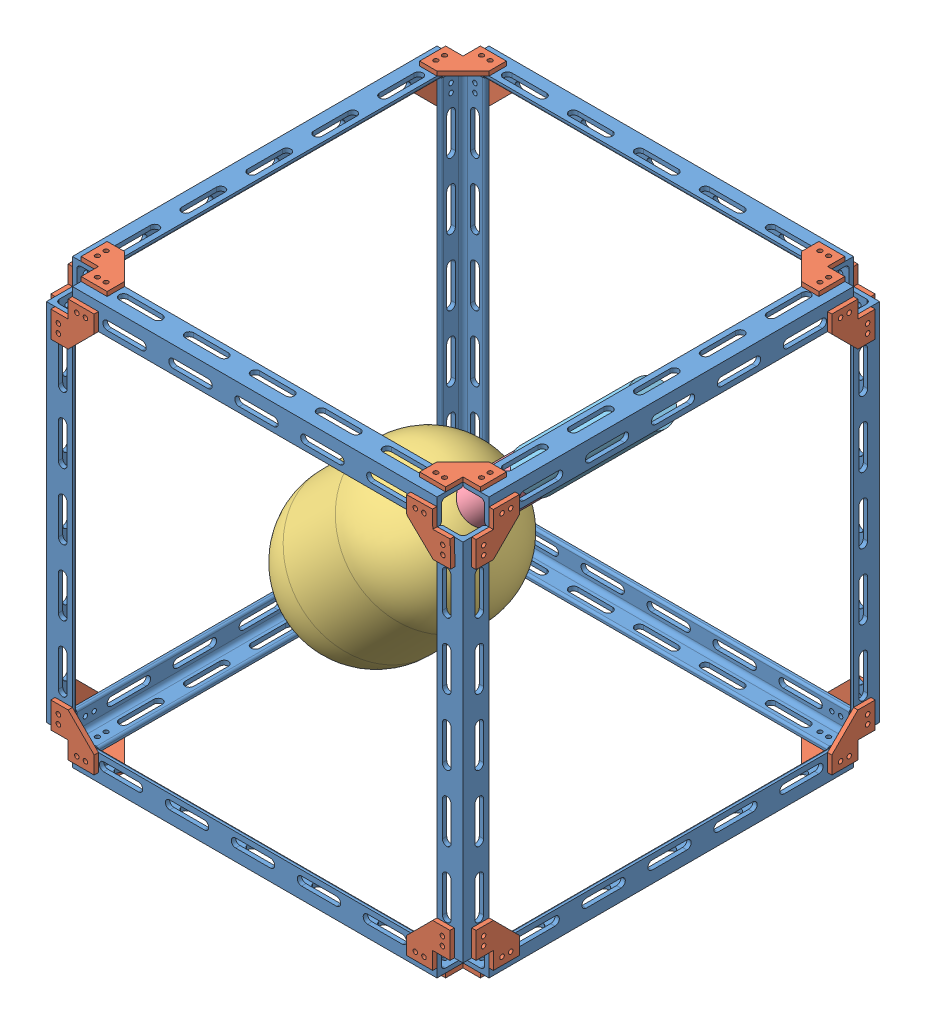
SolidWorks assembly 12 inch with Tank mated, configuration Default. Lengths in mm.
Overall size (334.91 334.91 311.15).
41 component instances, 5 part files, 4 mates.
Components (placement in the parent):
- Outer struct 12 in side length-1: Outer struct 12 in side length [Default] at (-152.3997 0 -152.3996) x (0 0 -1) z (1 0 0) size (311.15 311.15 311.15)
  - WIP 12 inch .75 L rod-1: WIP 12 inch .75 L rod [8982K281] at (-9.525 9.525 0) size (19.05 19.05 266.7)
  - WIP bracket for .75 L bar-1: WIP bracket for .75 L bar [Default] at (-44.4499 -3.175 -146.0502) x (1 0 0.000006) z (-0.000006 0 1) size (31.75 3.17 31.75)
  - WIP 12 inch .75 L rod-2: WIP 12 inch .75 L rod [8982K281] at (-152.4002 9.525 -142.8755) x (0 0 -1) z (1 0 0) size (19.05 19.05 266.7)
  - WIP 12 inch .75 L rod-3: WIP 12 inch .75 L rod [8982K281] at (-9.525 152.3996 -142.8755) x (1 0 0) z (0 -1 0) size (19.05 19.05 266.7)
  - WIP bracket for .75 L bar-2: WIP bracket for .75 L bar [Default] at (0 44.4494 -146.0507) x (0 -1 0.000022) z (0 0.000022 1) size (31.75 3.17 31.75)
  - WIP bracket for .75 L bar-3: WIP bracket for .75 L bar [Default] at (-44.4504 6.3501 -152.4005) x (1 -0.000015 0) z (0.000015 1 0) size (31.75 3.17 31.75)
  - WIP bracket for .75 L bar-4: WIP bracket for .75 L bar [Default] at (-260.3502 298.4499 -152.4005) x (-1 0 0) z (0 -1 0) size (31.75 3.17 31.75)
  - WIP bracket for .75 L bar-5: WIP bracket for .75 L bar [Default] at (-304.8002 260.35 -146.0506) x (0 1 0.000002) z (0 -0.000002 1) size (31.75 3.17 31.75)
  - WIP bracket for .75 L bar-6: WIP bracket for .75 L bar [Default] at (-260.3502 307.9748 -146.0505) x (-1 0 0) z (0 0 1) size (31.75 3.17 31.75)
  - WIP 12 inch .75 L rod-4: WIP 12 inch .75 L rod [8982K281] at (-152.4002 295.2748 -142.8755) x (0 0 -1) z (-1 0 0) size (19.05 19.05 266.7)
  - WIP 12 inch .75 L rod-5: WIP 12 inch .75 L rod [8982K281] at (-295.2752 295.2748 -0.0005) x (-1 0 0) z (0 0 1) size (19.05 19.05 266.7)
  - WIP 12 inch .75 L rod-6: WIP 12 inch .75 L rod [8982K281] at (-295.2752 152.3999 -142.8755) x (-1 0 0) z (0 1 0) size (19.05 19.05 266.7)
  - WIP bracket for .75 L bar-8: WIP bracket for .75 L bar [Default] at (-6.3503 260.3499 -152.4005) x (0.000002 1 0) z (-1 0.000002 0) size (31.75 3.17 31.75)
  - WIP bracket for .75 L bar-9: WIP bracket for .75 L bar [Default] at (-298.4502 44.4499 -152.4005) x (0 -1 0) z (1 0 0) size (31.75 3.17 31.75)
  - WIP bracket for .75 L bar-11: WIP bracket for .75 L bar [Default] at (-6.3505 304.8004 107.9491) x (0.000026 0 1) z (-1 0 0.000026) size (31.75 3.17 31.75)
  - WIP bracket for .75 L bar-12: WIP bracket for .75 L bar [Default] at (-44.4496 298.4506 152.3997) x (1 -0.000013 0) z (-0.000013 -1 0) size (31.75 3.17 31.75)
  - WIP 12 inch .75 L rod-7: WIP 12 inch .75 L rod [8982K281] at (-152.3996 295.2754 142.8747) x (0 0 1) z (1 0 0) size (19.05 19.05 266.7)
  - WIP 12 inch .75 L rod-8: WIP 12 inch .75 L rod [8982K281] at (-9.525 295.2748 -0.0008) x (0 1 0) z (0 0 1) size (19.05 19.05 266.7)
  - WIP bracket for .75 L bar-13: WIP bracket for .75 L bar [Default] at (3.175 298.4493 107.9491) x (0 0.000026 1) z (0 -1 0.000026) size (31.75 3.17 31.75)
  - WIP 12 inch .75 L rod-9: WIP 12 inch .75 L rod [8982K281] at (-9.525 152.4002 142.8747) x (0 0 1) z (0 -1 0) size (19.05 19.05 266.7)
  - WIP bracket for .75 L bar-14: WIP bracket for .75 L bar [Default] at (3.175 260.3496 -146.0505) x (0 1 -0.000009) z (0 0.000009 1) size (31.75 3.17 31.75)
  - WIP bracket for .75 L bar-15: WIP bracket for .75 L bar [Default] at (-298.4499 307.9754 107.9499) x (0.000007 0 1) z (1 0 -0.000007) size (31.75 3.17 31.75)
  - WIP bracket for .75 L bar-16: WIP bracket for .75 L bar [Default] at (-44.4503 304.7998 -146.0503) x (1 0 -0.000013) z (0.000013 0 1) size (31.75 3.17 31.75)
  - WIP bracket for .75 L bar-17: WIP bracket for .75 L bar [Default] at (-6.3497 -3.175 107.9497) x (0.000002 0 1) z (-1 0 0.000002) size (31.75 3.17 31.75)
  - WIP bracket for .75 L bar-18: WIP bracket for .75 L bar [Default] at (3.175 44.4503 146.0496) x (0 -1 0.000013) z (0 -0.000013 -1) size (31.75 3.17 31.75)
  - WIP bracket for .75 L bar-19: WIP bracket for .75 L bar [Default] at (-298.4492 260.3501 152.3997) x (-0.000013 1 0) z (1 0.000013 0) size (31.75 3.17 31.75)
  - WIP bracket for .75 L bar-20: WIP bracket for .75 L bar [Default] at (-304.8002 298.2273 107.8544) x (0 0.017459 0.999848) z (0 -0.999848 0.017459) size (31.75 3.17 31.75)
  - WIP bracket for .75 L bar-21: WIP bracket for .75 L bar [Default] at (-304.7994 44.4499 146.0495) x (0 -1 0) z (0 0 -1) size (31.75 3.17 31.75)
  - WIP 12 inch .75 L rod-11: WIP 12 inch .75 L rod [8982K281] at (-295.2744 152.4002 142.8747) x (-1 0 0) z (0 -1 0) size (19.05 19.05 266.7)
  - WIP bracket for .75 L bar-22: WIP bracket for .75 L bar [Default] at (-260.3497 6.3497 152.3997) x (-1 0.000013 0) z (0.000013 1 0) size (31.75 3.17 31.75)
  - WIP 12 inch .75 L rod-12: WIP 12 inch .75 L rod [8982K281] at (-152.3996 9.525 142.8747) x (0 0 1) z (-1 0 0) size (19.05 19.05 266.7)
  - WIP bracket for .75 L bar-23: WIP bracket for .75 L bar [Default] at (-260.3497 -3.175 146.05) x (-1 0 -0.000013) z (0.000013 0 -1) size (31.75 3.17 31.75)
  - WIP 12 inch .75 L rod-13: WIP 12 inch .75 L rod [8982K281] at (-295.2744 9.525 -0.0004) x (-1 0 0) z (0 0 -1) size (19.05 19.05 266.7)
  - WIP bracket for .75 L bar-24: WIP bracket for .75 L bar [Default] at (-304.8002 6.35 -107.9505) x (0 -0.000004 -1) z (0 1 -0.000004) size (31.75 3.17 31.75)
  - WIP bracket for .75 L bar-25: WIP bracket for .75 L bar [Default] at (-298.4495 -3.175 -107.95) x (-0.000022 0 -1) z (1 0 -0.000022) size (31.75 3.17 31.75)
  - WIP bracket for .75 L bar-26: WIP bracket for .75 L bar [Default] at (-6.3501 44.4503 152.3997) x (0.000013 -1 0) z (-1 -0.000013 0) size (31.75 3.17 31.75)
- LoFi Tank+Reg-1: LoFi Tank+Reg [Default] at (-196.8537 107.9466 0.0003) x (-0.041969 0.041971 0.998237) z (-0.707107 -0.707107 0.000001) size (111.12 111.12 340.27)
  - LoFi Tank-1: LoFi Tank [Default] at origin size (111.12 111.12 163.23)
  - LoFi Reg 1-1: LoFi Reg 1 [Default] at (0 0 -80.6816) x (-0.38598 0.922507 0) z (-0.922507 -0.38598 0) size (28.57 57.15 28.57)
  - LoFi Reg 2-1: LoFi Reg 2 [Default] at (0 0 -137.8316) x (-0.99247 0.12249 0) z (-0.12249 -0.99247 0) size (30.16 119.89 30.16)
Mates (geometry in assembly coordinates):
- Coincident3: coordinate: point of Outer struct 12 in side length-1/WIP 12 inch .75 L rod-12
- Coincident4: coincident: line of Outer struct 12 in side length-1/WIP 12 inch .75 L rod-7; line of LoFi Tank+Reg-1 through (4.238 309.0384 0) axis (-0.707107 -0.707107 0.000001)
- Coincident5: coincident: unknown of Outer struct 12 in side length-1/WIP 12 inch .75 L rod-2; line of LoFi Tank+Reg-1 through (4.238 309.0384 0) axis (-0.707107 -0.707107 0.000001)
- Lock1: lock: unknown of Outer struct 12 in side length-1/WIP 12 inch .75 L rod-7; unknown of LoFi Tank+Reg-1/LoFi Reg 2-1
